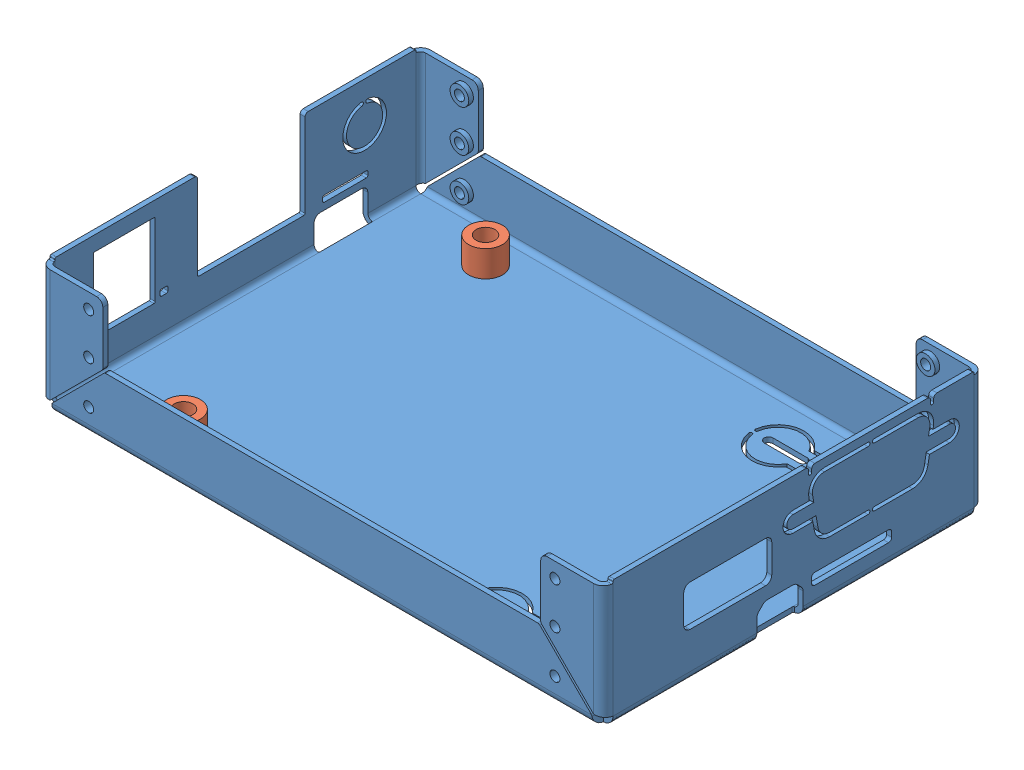
SolidWorks assembly Chassis_bottom_assembly, configuration Default. Lengths in mm.
Overall size (89.97 20.42 60.79).
5 component instances, 2 part files, 8 mates.
Components (placement in the parent):
- Chassis_bottom-1: Chassis_bottom [Default] at (34.5147 38.3972 77.4532) size (89.97 20.42 60.79)
- Chassis_PEM-1: Chassis_PEM [Default] at (72.1997 37.5972 56.4982) size (7.39 5 6.4)
- Chassis_PEM-2: Chassis_PEM [Default] at (72.1997 37.5972 98.4082) size (7.39 5 6.4)
- Chassis_PEM-3: Chassis_PEM [Default] at (6.1597 37.5972 53.3232) size (7.39 5 6.4)
- Chassis_PEM-4: Chassis_PEM [Default] at (6.1597 37.5972 101.5832) size (7.39 5 6.4)
Mates (geometry in assembly coordinates):
- Coincident1: coincident aligned: plane of Chassis_PEM-1 through (74.0472 37.5972 59.6982) normal (0 -1 0); plane of Chassis_PEM-2 through (74.0472 37.5972 101.6082) normal (0 -1 0)
- Coincident2: coincident aligned: plane of Chassis_PEM-2 through (74.0472 37.5972 101.6082) normal (0 -1 0); plane of Chassis_PEM-3 through (8.0072 37.5972 56.5232) normal (0 -1 0)
- Coincident3: coincident aligned: plane of Chassis_PEM-3 through (8.0072 37.5972 56.5232) normal (0 -1 0); plane of Chassis_PEM-4 through (8.0072 37.5972 104.7832) normal (0 -1 0)
- Coincident4: coincident aligned: plane of Chassis_bottom-1 through (34.5147 37.5972 77.4532) normal (0 -1 0); plane of Chassis_PEM-4 through (8.0072 37.5972 104.7832) normal (0 -1 0)
- Concentric1: concentric anti-aligned: cylinder of Chassis_bottom-1 through (6.1597 37.5972 101.5832) axis (0 1 0) radius 2.55; cylinder of Chassis_PEM-4 through (6.1597 42.5972 101.5832) axis (0 -1 0) radius 2.695
- Concentric2: concentric anti-aligned: cylinder of Chassis_bottom-1 through (6.1597 37.5972 53.3232) axis (0 1 0) radius 2.55; cylinder of Chassis_PEM-3 through (6.1597 42.5972 53.3232) axis (0 -1 0) radius 2.695
- Concentric3: concentric anti-aligned: cylinder of Chassis_bottom-1 through (72.1997 37.5972 98.4082) axis (0 1 0) radius 2.55; cylinder of Chassis_PEM-2 through (72.1997 42.5972 98.4082) axis (0 -1 0) radius 2.695
- Concentric4: concentric anti-aligned: cylinder of Chassis_bottom-1 through (72.1997 37.5972 56.4982) axis (0 1 0) radius 2.55; cylinder of Chassis_PEM-1 through (72.1997 42.5972 56.4982) axis (0 -1 0) radius 2.695
